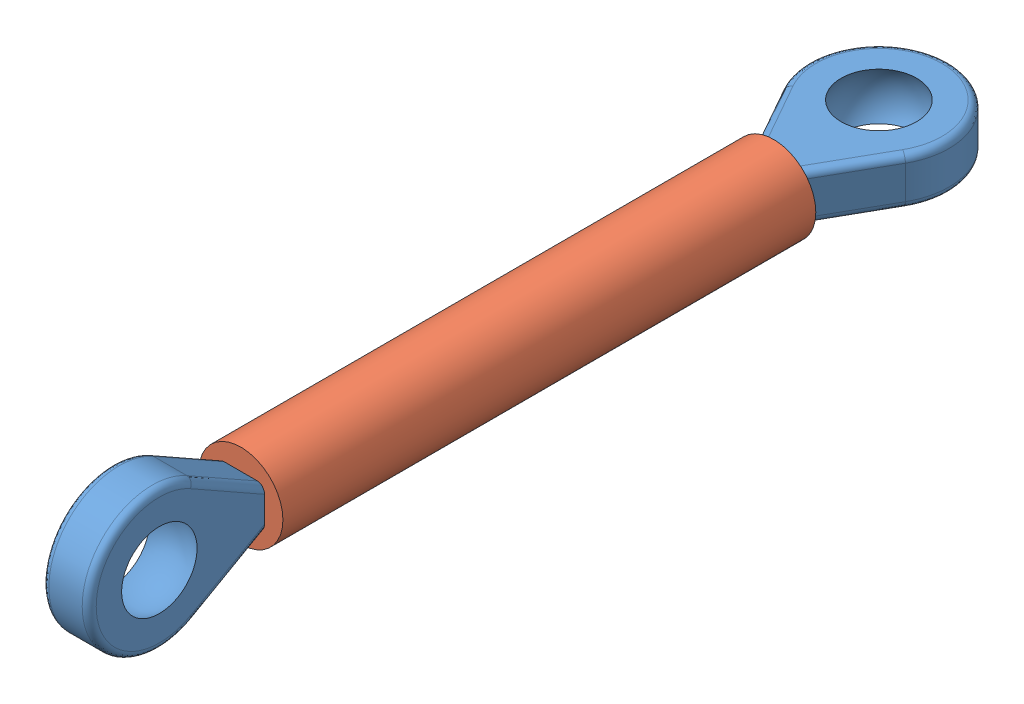
SolidWorks assembly 底盘-连杆系统, configuration 默认. Lengths in mm.
Overall size (20 20 126).
3 component instances, 2 part files, 5 mates.
Components (placement in the parent):
- 鱼眼轴承M6-1: 鱼眼轴承M6 [默认] at origin size (20 6.75 46)
- 铝柱 M6-1: 铝柱 M6 [默认] at (0 0 15) x (-1 0 0) z (0 0 1) size (12 12 76)
- 鱼眼轴承M6-2: 鱼眼轴承M6 [默认] at (0 0 106) x (0 -1 0) z (0 0 -1) size (20 6.75 46)
Mates (geometry in assembly coordinates):
- 重合2: coincident anti-aligned: plane of 鱼眼轴承M6-1 through (-3 3.375 15) normal (0 0 1); plane of 铝柱 M6-1 through (-17.8338 0 15) normal (0 0 -1)
- 重合3: coincident anti-aligned: plane of 铝柱 M6-1 through (-17.8338 0 91) normal (0 0 1); plane of 鱼眼轴承M6-2 through (-21.2088 3 91) normal (0 0 -1)
- 重合4: coincident anti-aligned: plane of 鱼眼轴承M6-1 through (0 0 0) normal (0 1 0); plane of 鱼眼轴承M6-2 through (-17.8338 0 106) normal (0 -1 0)
- 同心1: concentric aligned: cylinder of 铝柱 M6-1 through (-17.8338 0 91) axis (0 0 1) radius 2.5; cylinder of 鱼眼轴承M6-2 through (-17.8338 0 70) axis (0 0 1) radius 3
- 同心2: concentric aligned: cylinder of 鱼眼轴承M6-1 through (0 0 36) axis (0 0 -1) radius 3; cylinder of 铝柱 M6-1 through (-17.8338 0 15) axis (0 0 -1) radius 2.5
